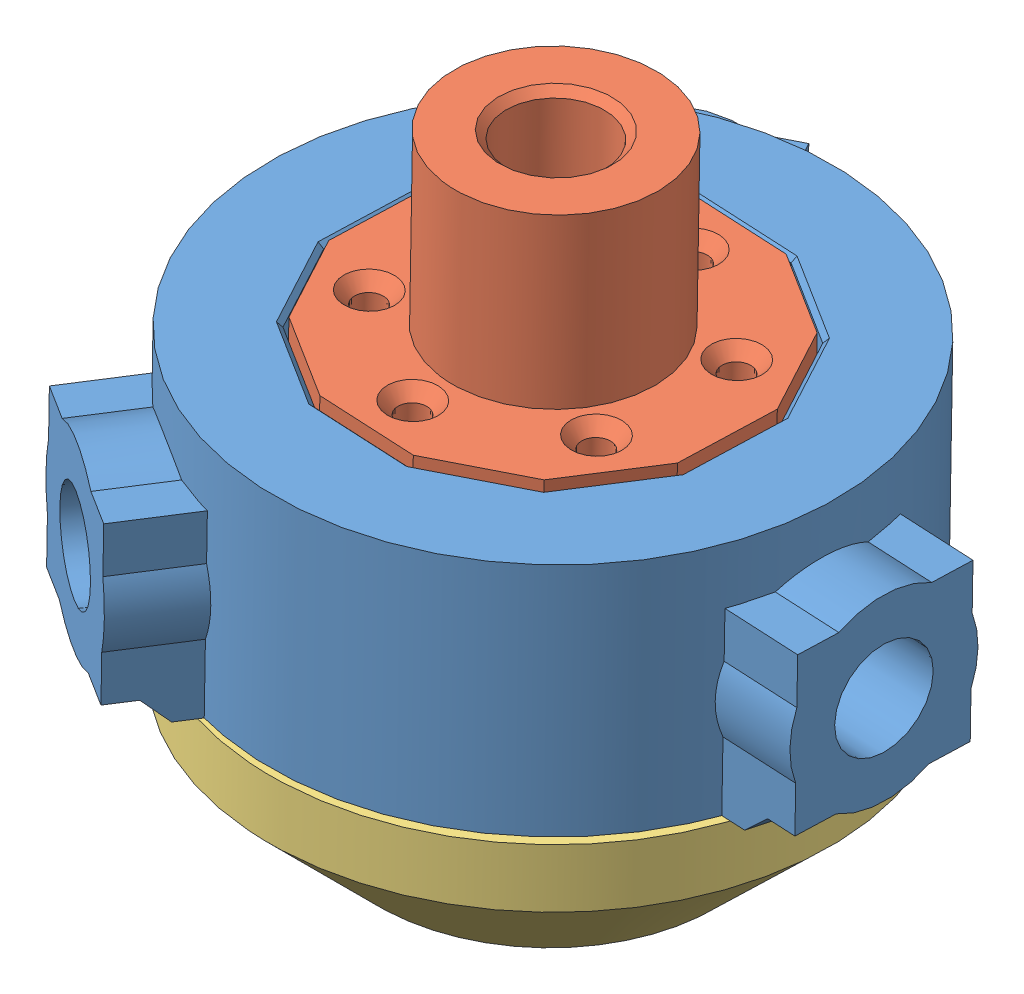
SolidWorks assembly Assembly_Pintle_V3_MJP, configuration Default. Lengths in mm.
Overall size (73.57 67.23 79.62).
3 component instances, 3 part files, 5 mates.
Components (placement in the parent):
- Part_annulus_base_v3_mjp-1: Part_annulus_base_v3_mjp [Default] at (-0.5044 -39.9586 0) x (0.99929 -0.017443 0.033397) z (-0.033392 0.000583 0.999442) size (70.48 31.75 77.31)
- Part_V3_Pintle_MJP-1: Part_V3_Pintle_MJP [Default] at (-0.5658 -43.4788 0) x (0.99929 -0.017443 0.033397) z (-0.033392 0.000583 0.999442) size (40.51 65.41 40.51)
- Part_mjp_support-1: Part_mjp_support [Default] at (-0.429 -35.6413 0) x (-0.999848 0.017452 0) z (0 0 1) size (63.5 19.33 63.5)
Mates (geometry in assembly coordinates):
- Concentric1: concentric: cylinder of Part_annulus_base_v3_mjp-1 through (-0.0611 -14.5625 0) axis (-0.017452 -0.999848 0) radius 6.4135; cylinder of Part_V3_Pintle_MJP-1 through (-0.0522 -14.0545 0) axis (-0.017452 -0.999848 0) radius 6.2865
- Concentric2: concentric: cylinder of Part_annulus_base_v3_mjp-1 through (-13.5975 -19.661 7.175) axis (0.017452 0.999848 0) radius 1.524; cylinder of Part_V3_Pintle_MJP-1 through (-13.3847 -7.4709 7.175) axis (0.017452 0.999848 0) radius 1.632
- Distance1: distance = 0.508 mm: plane of Part_annulus_base_v3_mjp-1 through (-0.0611 -14.5625 0) normal (0.017452 0.999848 0); plane of Part_V3_Pintle_MJP-1 through (-0.0522 -14.0545 0) normal (-0.017452 -0.999848 0)
- Concentric3: concentric: cylinder of Part_V3_Pintle_MJP-1 through (-0.4225 -35.2644 0) axis (0.017452 0.999848 0) radius 5.3467; cylinder of Part_mjp_support-1 through (-0.7664 -54.9677 0) axis (0.017452 0.999848 0) radius 5.715
- Distance2: distance = 0.762 mm: plane of Part_mjp_support-1 through (-0.429 -35.6413 0) normal (0.017452 0.999848 0); plane of Part_annulus_base_v3_mjp-1 through (-0.4157 -34.8794 0) normal (-0.017452 -0.999848 0)
